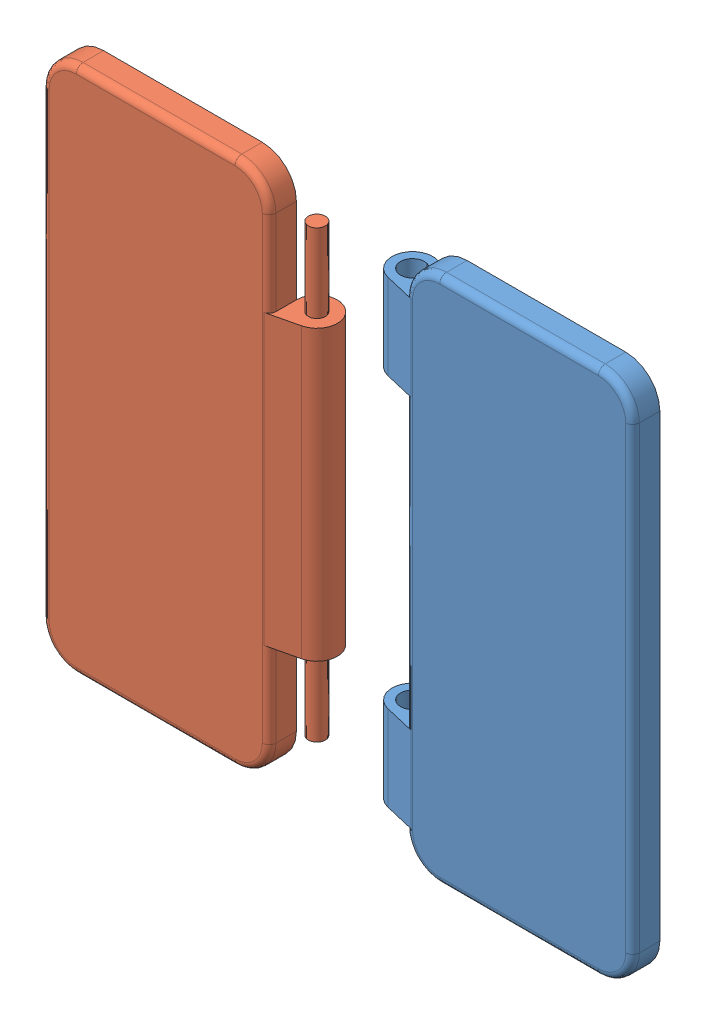
SolidWorks assembly MIRROR, configuration Default. Lengths in mm.
Overall size (173 154.5 14).
2 component instances, 2 part files, 0 mates.
Components (placement in the parent):
- Case-1: Case [Default] at (56.2351 28.2631 154.9245) size (78.5 154.5 14)
- MirrorCase-2: MirrorCase [Default] at (-89.7649 28.2631 154.9245) x (-1 0 0) z (0 0 -1) size (78.5 154.5 14)
